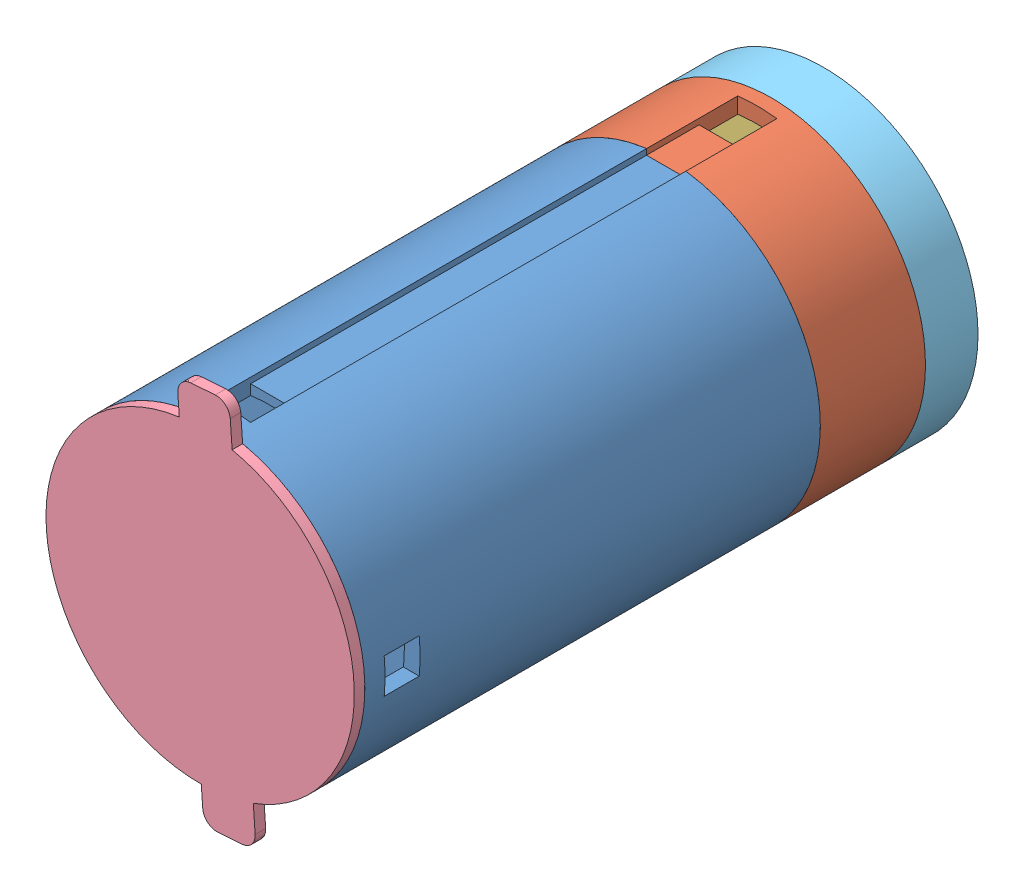
SolidWorks assembly SmartCupAssembly, configuration Default. Lengths in mm.
Overall size (140 140 241.66).
5 component instances, 5 part files, 21 mates.
Components (placement in the parent):
- MiddleCup-1: MiddleCup [Default] at (-48.6888 -12.1395 61.558) size (88 88 130)
- CupTop_PlaceUltrasonic-1: CupTop_PlaceUltrasonic [Default] at (-48.6854 -12.1395 202.558) x (1 0 0) z (0 1 0) size (140 155 140)
- UltrasonicTop-1: UltrasonicTop [Default] at (-48.6854 -12.1395 34.558) x (-1 0 0) z (0 -1 0) size (78 8 43.6)
- Bottom-1: Bottom [Default] at (-48.6888 -12.1395 194.558) x (-0.997444 -0.071447 0) z (0.071447 -0.997444 0) size (88 8 107.5)
- CupLid-1: CupLid [Default] at (-48.6854 -12.1395 16.558) x (-0.999391 -0.034899 0) z (-0.034899 0.999391 0) size (88 83.66 88)
Mates (geometry in assembly coordinates):
- Concentric1: concentric anti-aligned: cylinder of new-cup1-1 through (-47.7928 -15.8049 195) axis (0 0 -1) radius 44; cylinder of CupTop-1 through (-47.7928 -15.8049 26) axis (0 0 1) radius 44
- Coincident1: coincident anti-aligned: plane of new-cup1-1 through (-47.7928 -15.8049 65) normal (0 0 -1); plane of CupTop-1 through (-47.7928 -15.8049 65) normal (0 0 1)
- Parallel1: parallel aligned: plane of new-cup1-1 through (-53.3893 119.1951 189.1784) normal (1 0 0); plane of CupTop-1 through (-53.3928 37.8951 193.5439) normal (1 0 0)
- Concentric2: concentric aligned: cylinder of new-cup1-1 through (-47.7928 -15.8049 190) axis (0 0 1) radius 40.5; cylinder of 杯底-1 through (-47.7928 -15.8049 190) axis (0 0 1) radius 40.6
- Coincident3: coincident anti-aligned: plane of new-cup1-1 through (-62.3286 24.132 190) normal (-0.939693 -0.34202 0); plane of 杯底-1 through (-61.6788 22.3466 190) normal (0.939693 0.34202 0)
- Coincident4: coincident anti-aligned: plane of new-cup1-1 through (-47.7928 -15.8049 195) normal (0 0 1); plane of 杯底-1 through (-47.7928 -15.8049 195) normal (0 0 -1)
- Concentric4: concentric aligned: cylinder of yyy-1 through (-47.7928 -15.8049 29) axis (0 0 1) radius 38.5; cylinder of CupTop-1 through (-47.7928 -15.8049 66) axis (0 0 1) radius 39.5
- Coincident8: coincident anti-aligned: plane of CupTop-1 through (-47.7928 -15.8049 32) normal (0 0 -1); plane of yyy-1 through (-47.7928 -15.8049 32) normal (0 0 1)
- Parallel2: parallel anti-aligned: plane of CupTop-1 through (-12.7928 -19.0733 37) normal (0 1 0); plane of yyy-1 through (-13.7928 -19.0049 37) normal (0 -1 0)
- Coincident9: coincident anti-aligned: plane of CupTop-1 through (-48.6854 -12.1395 39.558) normal (0 0 -1); plane of yyy-1 through (-48.6854 -12.1395 39.558) normal (0 0 1)
- Concentric5: concentric anti-aligned: circle of CupTop-1; circle of yyy-1
- Coincident11: coincident anti-aligned: plane of CupTop-1 through (-48.6854 -12.1395 36.558) normal (0 0 -1); plane of 杯底 - 副本-1 through (-48.6854 -12.1395 36.558) normal (0 0 1)
- Coincident13: coincident anti-aligned: plane of CupTop-1 through (-34.1496 27.7974 36.558) normal (0.939693 -0.34202 0); plane of 杯底 - 副本-1 through (-34.7652 26.106 36.558) normal (-0.939693 0.34202 0)
- Concentric7: concentric anti-aligned: cylinder of CupTop-1 through (-48.6854 -12.1395 22.558) axis (0 0 1) radius 44; cylinder of 杯底 - 副本-1 through (-48.6854 -12.1395 31.558) axis (0 0 -1) radius 44
- Coincident14: coincident aligned: plane of new-cup1-1 through (-54.2854 124.8605 185.7363) normal (1 0 0); plane of CupTop-1 through (-54.2854 43.4605 192.2605) normal (1 0 0)
- Coincident15: coincident aligned: plane of new-cup1-1 through (-48.6888 29.8605 61.558) normal (0 1 0); plane of CupTop-1 through (-48.6854 29.8605 202.558) normal (0 1 0)
- Coincident16: coincident anti-aligned: plane of new-cup1-1 through (-48.6888 -12.1395 61.558) normal (0 0 -1); plane of CupTop-1 through (-48.6854 -12.1395 61.558) normal (0 0 1)
- Coincident17: coincident anti-aligned: plane of new-cup1-1 through (-48.6888 -12.1395 191.558) normal (0 0 1); plane of 杯底-1 through (-48.6888 -12.1395 191.558) normal (0 0 -1)
- Coincident18: coincident anti-aligned: plane of new-cup1-1 through (-63.2247 27.7974 186.558) normal (-0.939693 -0.34202 0); plane of 杯底-1 through (-62.6091 26.106 186.558) normal (0.939693 0.34202 0)
- Concentric8: concentric anti-aligned: cylinder of new-cup1-1 through (-48.6888 -12.1395 191.558) axis (0 0 -1) radius 44; cylinder of 杯底-1 through (-48.6888 -12.1395 191.558) axis (0 0 1) radius 44
- Parallel3: parallel anti-aligned: plane of CupTop-1 through (-13.6854 -15.4079 39.558) normal (0 1 0); plane of yyy-1 through (-14.6854 -15.3395 39.558) normal (0 -1 0)
